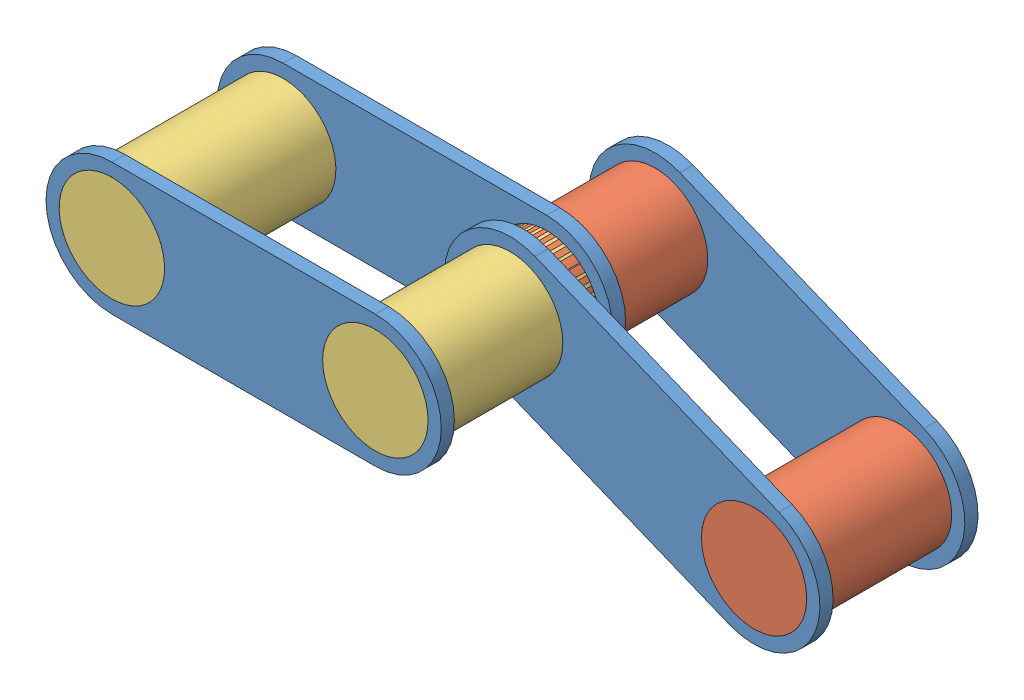
SolidWorks assembly ChainPattern, configuration Default. Lengths in mm.
Overall size (63.55 26.15 28.22).
10 component instances, 3 part files, 1 mates.
Components (placement in the parent):
- SmallLinkageChain-2: SmallLinkageChain [Default] at (10.8154 6.7125 -9.6495) x (0.925931 -0.377692 0) z (0 0 1) size (38.1 12.7 15.24)
  - LinkagePart-1: LinkagePart [Default] at (73.4379 54.8795 -38.979) size (38.1 12.7 1.27)
  - SmallLinkCylinder-1: SmallLinkCylinder [Default] at (24.7536 -17.0726 -38.979) size (10.16 10.16 15.24)
  - SmallLinkCylinder-2: SmallLinkCylinder [Default] at (-0.6464 -17.0726 -38.979) size (10.16 10.16 15.24)
  - LinkagePart-2: LinkagePart [Default] at (73.4379 54.8795 -25.009) size (38.1 12.7 1.27)
- LargeLinkageChain-1: LargeLinkageChain [Default] at (-24.1386 -10.0836 -53.0398) size (38.1 12.71 17.78)
  - LinkagePart-1: LinkagePart [Default] at (82.5888 75.7448 31.3654) size (38.1 12.7 1.27)
  - LargeLinkCylinder-1: LargeLinkCylinder [Default] at (-0.7371 26.0172 14.8554) x (0.034703 0.999398 0) z (0 0 1) size (10.16 10.16 17.78)
  - LargeLinkCylinder-2: LargeLinkCylinder [Default] at (16.5252 20.2309 14.8554) x (-0.955371 0.295407 0) z (0 0 1) size (10.16 10.16 17.78)
  - LinkagePart-2: LinkagePart [Default] at (82.5888 75.7448 14.8554) size (38.1 12.7 1.27)
Mates (geometry in assembly coordinates):
- Concentric1: concentric aligned: cylinder of SmallLinkageChain-2/SmallLinkCylinder-2 through (0.239 7.7193 -33.3885) axis (0 0 -1) radius 5.08; cylinder of LargeLinkageChain-1/LargeLinkCylinder-2 through (0.239 7.7193 -20.4043) axis (0 0 -1) radius 5.08
